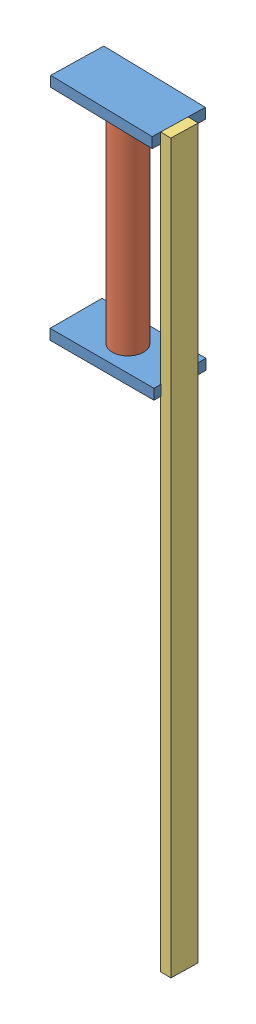
SolidWorks assembly Assem1, configuration Default. Lengths in mm.
Overall size (110.73 700 52.25).
4 component instances, 3 part files, 8 mates.
Components (placement in the parent):
- connector1-1: connector1 [Default] at (-34.8415 55.3733 111.4165) x (0.999745 0 0.022588) z (-0.022588 0 0.999745) size (100 10 50)
- cylinder1-1: cylinder1 [Default] at (8.8006 -144.6267 88.5192) size (30 200 30)
- connector1-2: connector1 [Default] at (-34.3131 -154.6267 112.3965) size (100 10 50)
- long connector-1: long connector [Default] at (67.4106 -579.6191 150.7186) x (-0.022588 0 0.999745) z (-0.999745 0 -0.022588) size (25.74 700 10)
Mates (geometry in assembly coordinates):
- Coincident1: coincident anti-aligned: plane of connector1-1 through (-34.8415 55.3733 111.4165) normal (0 -1 0); plane of cylinder1-1 through (8.8006 55.3733 88.5192) normal (0 1 0)
- Width1: width: cylinder of connector1-1; plane of cylinder1-1 through (-40.6219 65.3733 62.3962) normal (0.022588 0 -0.999745); cylinder of connector1-1 through (8.8006 55.3733 88.5192) axis (0 -1 0) radius 15
- Width2: width: plane of connector1-1 through (59.3526 65.3733 64.655) normal (0.999745 0 0.022588); plane of cylinder1-1 through (-40.6219 65.3733 62.3962) normal (-0.999745 0 -0.022588); cylinder of connector1-1 through (8.8006 55.3733 88.5192) axis (0 -1 0) radius 15
- Coincident2: coincident anti-aligned: plane of cylinder1-1 through (8.8006 -144.6267 88.5192) normal (0 -1 0); plane of connector1-2 through (-34.3131 -144.6267 112.3965) normal (0 1 0)
- Width3: width: plane of connector1-2 through (-41.1994 -144.6267 113.5192) normal (0 0 1); plane of cylinder1-1 through (-41.1994 -144.6267 63.5192) normal (0 0 -1); cylinder of connector1-2 through (8.8006 55.3733 88.5192) axis (0 -1 0) radius 15
- Width4: width: plane of connector1-2 through (58.8006 -144.6267 63.5192) normal (1 0 0); plane of cylinder1-1 through (-41.1994 -144.6267 63.5192) normal (-1 0 0); cylinder of connector1-2 through (8.8006 55.3733 88.5192) axis (0 -1 0) radius 15
- Coincident3: coincident anti-aligned: plane of connector1-1 through (59.3526 65.3733 64.655) normal (0.999745 0 0.022588); plane of long connector-1 through (57.4132 -579.6191 150.4928) normal (-0.999745 0 -0.022588)
- Coincident4: coincident aligned: plane of connector1-1 through (-34.8415 65.3733 111.4165) normal (0 1 0); plane of long connector-1 through (58.9845 65.3733 80.9467) normal (0 1 0)
